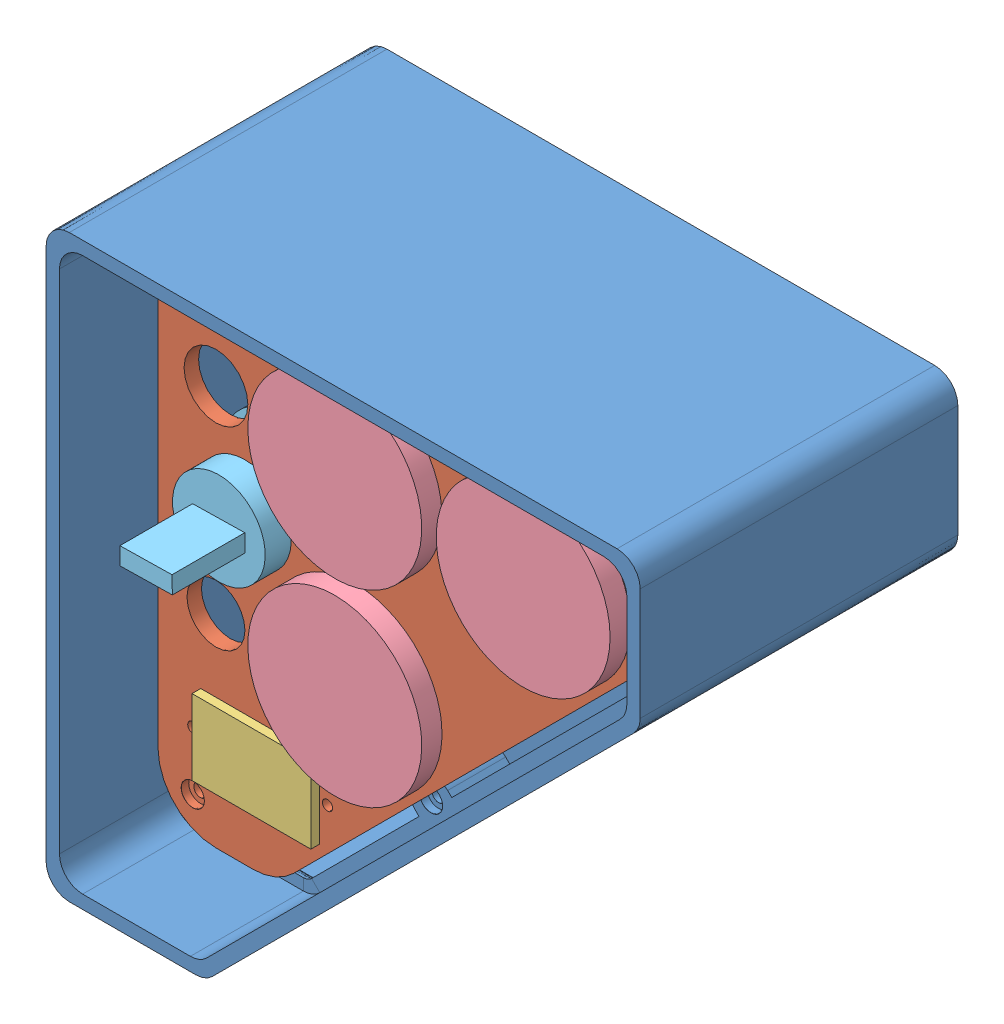
SolidWorks assembly prova3, configuration Default. Lengths in mm.
Overall size (205 200 109.7).
7 component instances, 5 part files, 14 mates.
Components (placement in the parent):
- base prova-1: base prova [Default] at (-164.1017 -121.59 -48.5) size (205 200 109.6)
- layer2-1: layer2 [Default] at (-159.5017 -114.19 22.1) size (183 188 5)
- scree-1: scree [Default] at (-124.2517 -82.19 -34.9) x (1 0 0) z (0 -1 0) size (41 65 26)
- tachi-1: tachi [Default] at (-91.5017 -41.19 -7.9) x (-0.151372 0.988477 0) z (0.988477 0.151372 0) size (60 42 60)
- tachi-2: tachi [Default] at (-91.5017 23.81 -7.9) x (-0.675444 0.737411 0) z (0.737411 0.675444 0) size (60 42 60)
- tachi-3: tachi [Default] at (-26.5017 23.81 -7.9) x (-0.676507 -0.736436 0) z (-0.736436 0.676507 0) size (60 42 60)
- chiave-1: chiave [Default] at (-129.5017 -9.19 -22.7) x (0.999831 0.018407 0) z (0.018407 -0.999831 0) size (45 83.9 45)
Mates (geometry in assembly coordinates):
- Coincidente1: coincident anti-aligned: plane of base prova-1 through (-151.5017 73.81 22.1) normal (0 0 1); plane of layer2-1 through (-139.5017 53.81 22.1) normal (0 0 -1)
- Coincidente2: coincident: plane of base prova-1 through (-159.5017 65.81 -39.9) normal (1 0 0); line of layer2-1 through (-159.5017 53.81 27.1) axis (0 -1 0)
- Coincidente3: coincident: plane of base prova-1 through (28.2983 73.81 -39.9) normal (0 -1 0); line of layer2-1 through (3.4983 73.81 27.1) axis (-1 0 0)
- Coincidente4: coincident anti-aligned: plane of layer2-1 through (-143.7517 -94.19 20.1) normal (1 0 0); plane of scree-1 through (-143.7517 -70.19 27.1) normal (-1 0 0)
- Coincidente5: coincident anti-aligned: plane of layer2-1 through (-143.7517 -70.19 20.1) normal (0 -1 0); plane of scree-1 through (-143.7517 -70.19 27.1) normal (0 1 0)
- Coincidente6: coincident: plane of layer2-1 through (-139.5017 53.81 27.1) normal (0 0 1); line of scree-1 through (-103.7517 -69.19 27.1) axis (-1 0 0)
- Concentrico1: concentric aligned: circle of layer2-1; circle of tachi-1
- Coincidente7: coincident aligned: plane of layer2-1 through (-139.5017 53.81 27.1) normal (0 0 1); circle of tachi-1
- Concentrico2: concentric aligned: circle of layer2-1; circle of tachi-2
- Coincidente8: coincident aligned: plane of layer2-1 through (-139.5017 53.81 27.1) normal (0 0 1); circle of tachi-2
- Concentrico3: concentric aligned: cylinder of layer2-1 through (-26.5017 23.81 20.1) axis (0 0 1) radius 26; circle of tachi-3
- Coincidente9: coincident aligned: plane of layer2-1 through (-139.5017 53.81 27.1) normal (0 0 1); circle of tachi-3
- Concentrico4: concentric aligned: circle of layer2-1; circle of chiave-1
- Coincidente10: coincident aligned: plane of layer2-1 through (-139.5017 53.81 27.1) normal (0 0 1); circle of chiave-1
